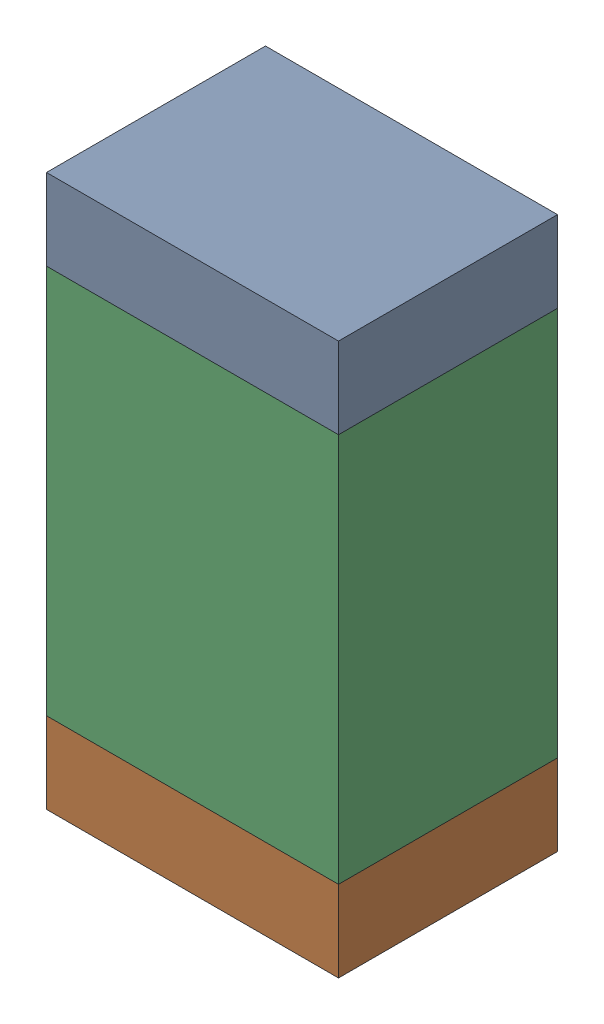
SolidWorks assembly C4, configuration 默认. Lengths in mm.
Overall size (1.8 3.4 1.35).
6 component instances, 2 part files, 0 mates.
Components (placement in the parent):
- 6241790576-1: 6241790576 [默认] at (18.923 18.595 -3.0414) size (1.8 0.5 1.35)
  - Extruded-2-1: Extruded-2 [默认] at origin size (1.8 0.5 1.35)
- 6241790576-2: 6241790576 [默认] at (18.923 15.695 -3.0414) size (1.8 0.5 1.35)
  - Extruded-2-1: Extruded-2 [默认] at origin size (1.8 0.5 1.35)
- 6241790896-1: 6241790896 [默认] at (18.923 17.145 -3.0414) size (1.8 2.4 1.35)
  - Extruded-3-1: Extruded-3 [默认] at origin size (1.8 2.4 1.35)
